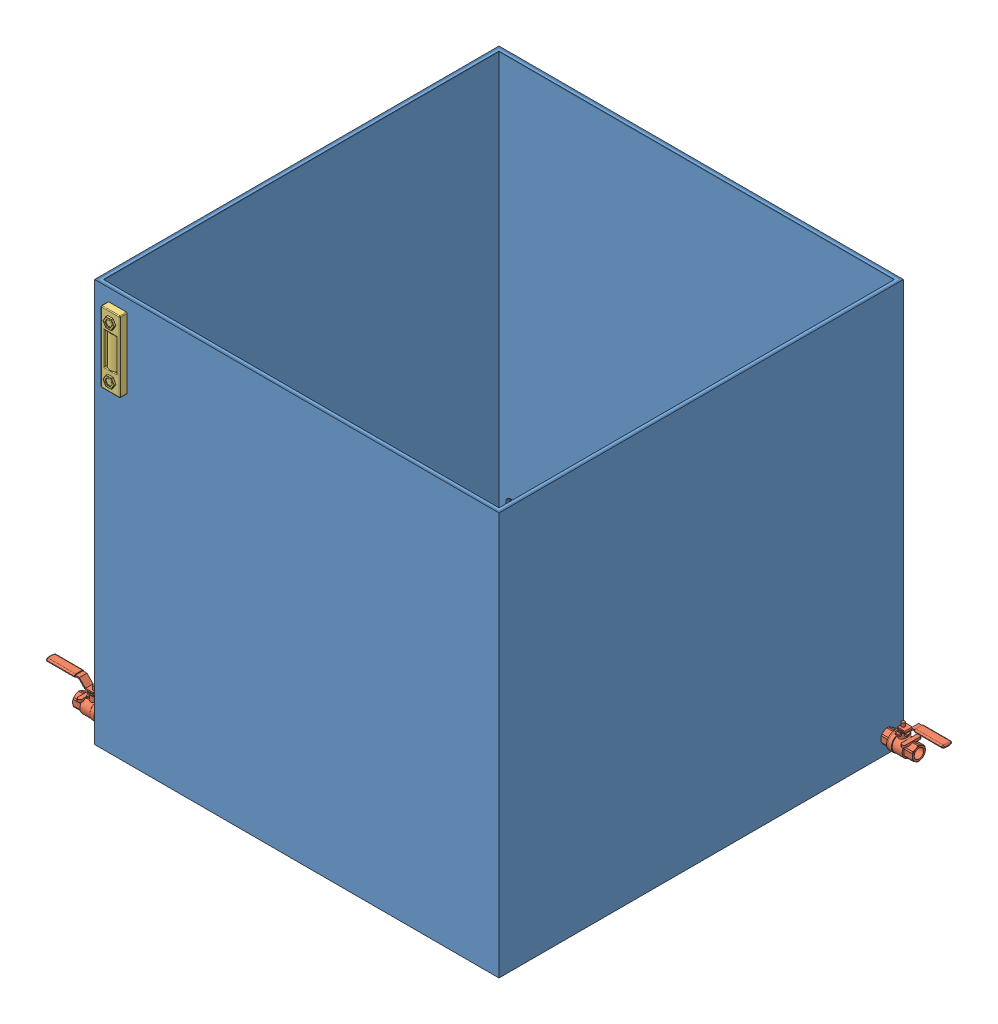
SolidWorks assembly Tank Assembly, configuration Default. Lengths in mm.
Overall size (1316.11 1008 1187.06).
5 component instances, 3 part files, 10 mates.
Components (placement in the parent):
- Tank-1: Tank [Default] at (-26.6088 -502.892 17.3646) size (1012 1008 1012)
- Ball Valve-1: Ball Valve [Default] at (558.3912 -468.892 -448.6354) x (-1 0 0) z (0 0 -1) size (152.06 78.56 45)
- Ball Valve-2: Ball Valve [Default] at (-611.6088 -468.892 483.3646) size (152.06 78.56 45)
- Ball Valve-3: Ball Valve [Default] at (-492.6088 -468.892 -567.6354) x (0 0 1) z (-1 0 0) size (152.06 78.56 45)
- Level Gauge-1: Level Gauge [Default] at (-475.284 379.7158 523.3646) size (48 177 23)
Mates (geometry in assembly coordinates):
- Coincident1: coincident: plane of assembly; plane of assembly; plane of Tank-1 through (479.3912 497.108 -482.6354) normal (1 0 0); plane of Ball Valve-1 through (479.3912 -468.892 -448.6354) normal (-1 0 0)
- Concentric1: concentric: cylinder of assembly; cylinder of assembly; cylinder of Tank-1 through (439.3912 -468.892 -448.6354) axis (1 0 0) radius 12; cylinder of Ball Valve-1 through (1558.3912 -468.892 -448.6354) axis (1 0 0) radius 12
- Parallel1: parallel: plane of assembly; plane of assembly; plane of Tank-1 through (-26.6088 -508.892 17.3646) normal (0 -1 0); plane of Ball Valve-1 through (558.4476 -418.3356 -440.3854) normal (0 -1 0)
- Coincident3: coincident: plane of assembly; plane of assembly; plane of Tank-1 through (-526.6088 497.108 -488.6354) normal (0 0 -1); plane of Ball Valve-3 through (-492.6088 -468.892 -488.6354) normal (0 0 1)
- Concentric2: concentric: cylinder of assembly; cylinder of assembly; cylinder of Tank-1 through (-492.6088 -468.892 -448.6354) axis (0 0 -1) radius 12; cylinder of Ball Valve-3 through (-492.6088 -468.892 -1567.6354) axis (0 0 -1) radius 12
- Parallel2: parallel: plane of assembly; plane of assembly; plane of Tank-1 through (-26.6088 -508.892 17.3646) normal (0 -1 0); plane of Ball Valve-3 through (-484.3588 -418.3356 -567.6917) normal (0 -1 0)
- Coincident5: coincident: plane of assembly; plane of assembly; plane of Tank-1 through (-532.6088 497.108 -482.6354) normal (-1 0 0); plane of Ball Valve-2 through (-532.6088 -468.892 483.3646) normal (1 0 0)
- Concentric3: concentric: cylinder of assembly; cylinder of assembly; cylinder of Tank-1 through (-492.6088 -468.892 483.3646) axis (-1 0 0) radius 12; cylinder of Ball Valve-2 through (-1611.6088 -468.892 483.3646) axis (-1 0 0) radius 12
- Parallel3: parallel: plane of assembly; plane of assembly; plane of Tank-1 through (-26.6088 -508.892 17.3646) normal (0 -1 0); plane of Ball Valve-2 through (-611.6651 -418.3356 475.1146) normal (0 -1 0)
- Coincident7: coincident: plane of assembly; plane of assembly; plane of Tank-1 through (-526.6088 497.108 523.3646) normal (0 0 1); plane of Level Gauge-1 through (-497.284 293.2158 523.3646) normal (0 0 -1)
